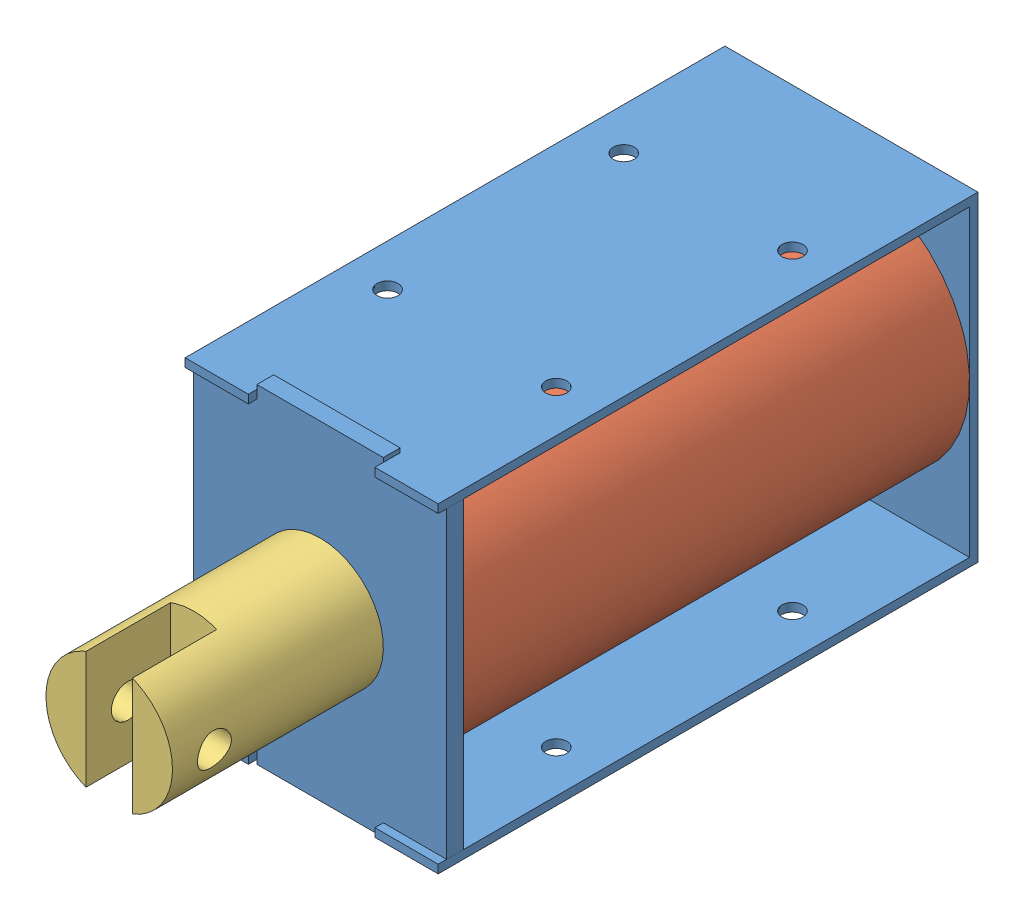
SolidWorks assembly Assem1, configuration Standard. Lengths in mm.
Overall size (37.21 39 88).
3 component instances, 3 part files, 6 mates.
Components (placement in the parent):
- Kaefig-1: Kaefig [Standard] at (-15 19 56.3919) x (0 -1 0) z (0 0 1) size (39 30 64)
- spule-1: spule [Standard] at (0 0 -6.6081) x (0.95985 0.280515 0) z (0 0 1) size (30 30 60)
- Stift-1: Stift [Default] at (0 0 55.3919) x (1 0 0) z (0 -1 0) size (15 25 15)
Mates (geometry in assembly coordinates):
- Coincident1: coincident anti-aligned: plane of Kaefig-1 through (16.7623 16.3715 -6.6081) normal (0 0 1); plane of spule-1 through (0 0 -6.6081) normal (0 0 -1)
- Coincident2: coincident aligned: line of spule-1 through (0 0 53.3919) axis (0 0 -1)
- Coincident4: coincident aligned: line of Kaefig-1 through (0 0 59.5919) axis (0 0 -1)
- Coincident5: coincident anti-aligned: plane of Kaefig-1 through (-12.9781 20.4345 55.3919) normal (0 0 1); plane of Stift-1 through (0 0 55.3919) normal (0 0 -1)
- Coincident6: coincident anti-aligned: line of Stift-1 through (0 0 54.1419) axis (0 0 1)
- Parallel1: parallel anti-aligned: plane of Kaefig-1 through (15 -19 -7.6081) normal (0 -1 0)
